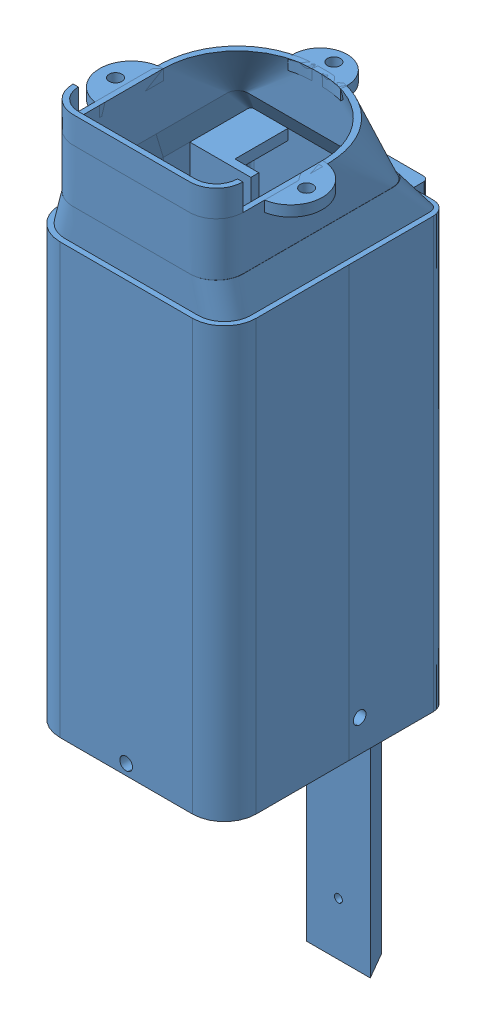
SolidWorks assembly nnx_cap_with_intan64_hs, configuration Default. Lengths in mm.
Overall size (21 80.99 28.5).
14 component instances, 9 part files, 3 mates.
Components (placement in the parent):
- nnx_cap_tall_longrear-1: nnx_cap_tall_longrear [Default] at origin size (21 80.99 28.5)
- Copy of RHD2164_headstage_bga.STEP^nnx_cap_with_intan64_hs-2: Copy of RHD2164_headstage_bga.STEP^nnx_cap_with_intan64_hs [Default] at (-6.985 -48.42 -7.722) size (13.97 24.45 4.89) (virtual)
  - RHD2164_headstage_bga_PCB.STEP-1: RHD2164_headstage_bga_PCB.STEP [Default] at origin size (13.97 20.1 0.91)
  - 0402c_2320560.STEP-1: 0402c_2320560.STEP [Default] at (13.0175 9.525 0.9144) x (0 1 0) z (0 0 1) size (1.15 0.6 0.55)
  - 0201c_0201.STEP-1: 0201c_0201.STEP [Default] at (12.5603 6.6167 1.0644) size (0.6 0.3 0.3)
  - 0402r_1430758.STEP-1: 0402r_1430758.STEP [Default] at (1.5621 9.779 0.9144) x (0 1 0) z (0 0 1) size (1.15 0.55 0.4)
  - 0402r_1430758.STEP-2: 0402r_1430758.STEP [Default] at (11.8128 5.2256 0.9144) x (-1 0 0) z (0 0 1) size (1.15 0.55 0.4)
  - 0201r_0201.STEP-1: 0201r_0201.STEP [Default] at (5.8532 4.3049 1.0294) x (-1 0 0) z (0 1 0) size (0.3 0.23 0.6)
  - 0201r_0201.STEP-2: 0201r_0201.STEP [Default] at (11.6205 1.4732 1.0294) x (1 0 0) z (0 -1 0) size (0.3 0.23 0.6)
  - 0201r_0201.STEP-3: 0201r_0201.STEP [Default] at (11.6205 3.3655 1.0294) x (-1 0 0) z (0 1 0) size (0.3 0.23 0.6)
  - A79025-001.STEP-1: A79025-001.STEP [Default] at (5.715 19.1516 2.6924) size (13.14 7.45 2.1)
  - A79025-001.STEP-2: A79025-001.STEP [Default] at (8.255 19.1516 -1.778) x (-1 0 0) z (0 0 -1) size (13.14 7.45 2.1)
  - A79623-001.STEP-1: A79623-001.STEP [Default] at (8.5598 2.6543 0.9144) x (1 0 0) z (0 -1 0) size (4.45 2.05 6.53)
  - RHD2164_bga.STEP-1: RHD2164_bga.STEP [Default] at (6.9977 9.5377 0.9144) size (9 7 1.2)
Mates (geometry in assembly coordinates):
- Distance1: distance = 0.03 mm aligned: plane of Copy of RHD2164_headstage_bga.STEP^nnx_cap_with_intan64_hs-2/RHD2164_headstage_bga_PCB.STEP-1 through (6.985 -48.42 -6.8076) normal (0 -1 0); plane of nnx_cap_tall_longrear-1 through (-6.2504 -48.45 7.5) normal (0 -1 0)
- Coincident7: coincident anti-aligned: unknown of Copy of RHD2164_headstage_bga.STEP^nnx_cap_with_intan64_hs-2
- Coincident8: coincident anti-aligned: plane of nnx_cap_tall_longrear-1 through (-7.95 -48.45 -9.5) normal (0 0 1); plane of Copy of RHD2164_headstage_bga.STEP^nnx_cap_with_intan64_hs-2/A79025-001.STEP-2 through (-6.5405 -30.5384 -9.5) normal (0 0 -1)
